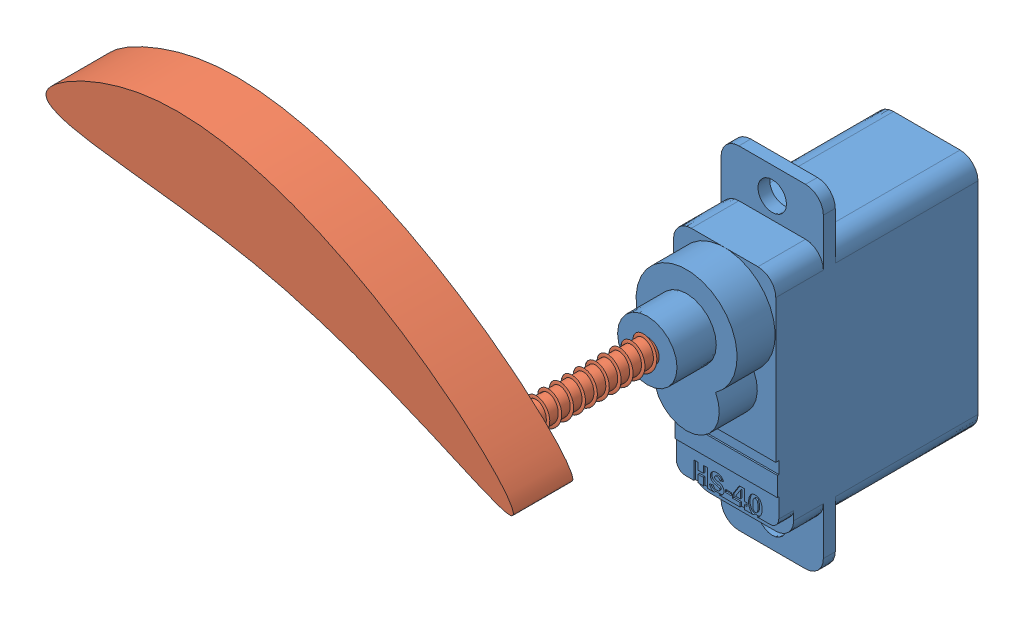
SolidWorks assembly Assem1, configuration Default. Lengths in mm.
Overall size (42.3 37.61 38.5).
2 component instances, 2 part files, 2 mates.
Components (placement in the parent):
- HS-40 servo-1: HS-40 servo [Default] at (12.729 16.0257 19.5802) x (1 0 0) z (0 -1 0) size (8.6 23.5 28)
- Eyebrow_Right (Actually)-1: Eyebrow_Right (Actually) [Default] at (-22.6535 30.6316 46.0802) x (0.944726 -0.32786 0) z (0 0 1) size (41.09 10.6 15)
Mates (geometry in assembly coordinates):
- Coincident1: coincident anti-aligned: plane of HS-40 servo-1 through (12.729 21.7757 31.0802) normal (0 0 1); circle of Eyebrow_Right (Actually)-1
- Concentric1: concentric anti-aligned: cylinder of HS-40 servo-1 through (12.729 21.7757 31.0802) axis (0 0 -1) radius 2.5; cylinder of Eyebrow_Right (Actually)-1 through (12.729 21.7757 31.0802) axis (0 0 1) radius 1
